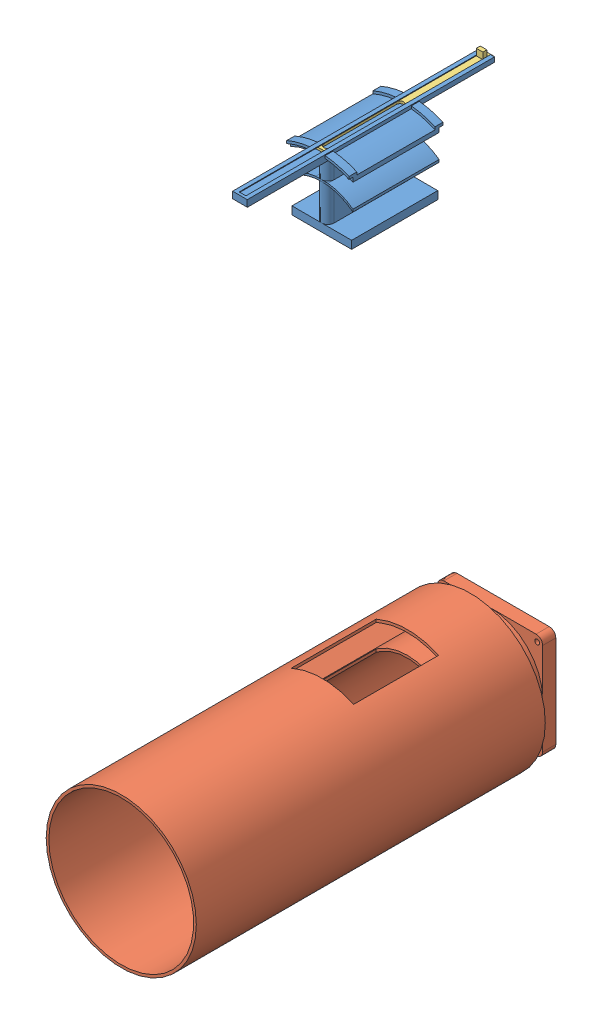
SolidWorks assembly Shell Assambled, configuration Default. Lengths in mm.
Overall size (114 467.47 298.21).
3 component instances, 3 part files, 7 mates.
Components (placement in the parent):
- Drawer-1: Drawer [Default] at (0 353.6848 100) x (-1 0 0) z (0 -1 0) size (47.3 187.8 55.29)
- Shell Sensors-1: Shell Sensors [KA8038HA] at origin size (114 114 290)
- CoverCable-1: CoverCable [Default] at (0 404.4725 40.8783) x (1 0 0) z (0 1 0) size (9.4 126.7 7.02)
Mates (geometry in assembly coordinates):
- Coincident1: coincident aligned: plane of Shell Sensors-1 through (0 0 0) normal (0 0 1)
- Coincident2: coincident aligned: plane of Shell Sensors-1 through (0 0 0) normal (0 1 0)
- Coincident3: coincident aligned: plane of Shell Sensors-1 through (0 0 0) normal (1 0 0)
- Coincident8: coincident anti-aligned: plane of Drawer-1 through (0 353.6848 100) normal (-1 0 0)
- Coincident9: coincident anti-aligned: plane of Drawer-1 through (0 353.6848 100) normal (0 0 -1)
- Coincident10: coincident anti-aligned: plane of Drawer-1 through (0 353.6848 100) normal (-1 0 0); plane of CoverCable-1 through (0 404.4725 40.8783) normal (1 0 0)
- Coincident11: coincident anti-aligned: plane of Drawer-1 through (0 405.4725 7.1) normal (0 -1 0); plane of CoverCable-1 through (0 405.4725 40.8783) normal (0 1 0)
